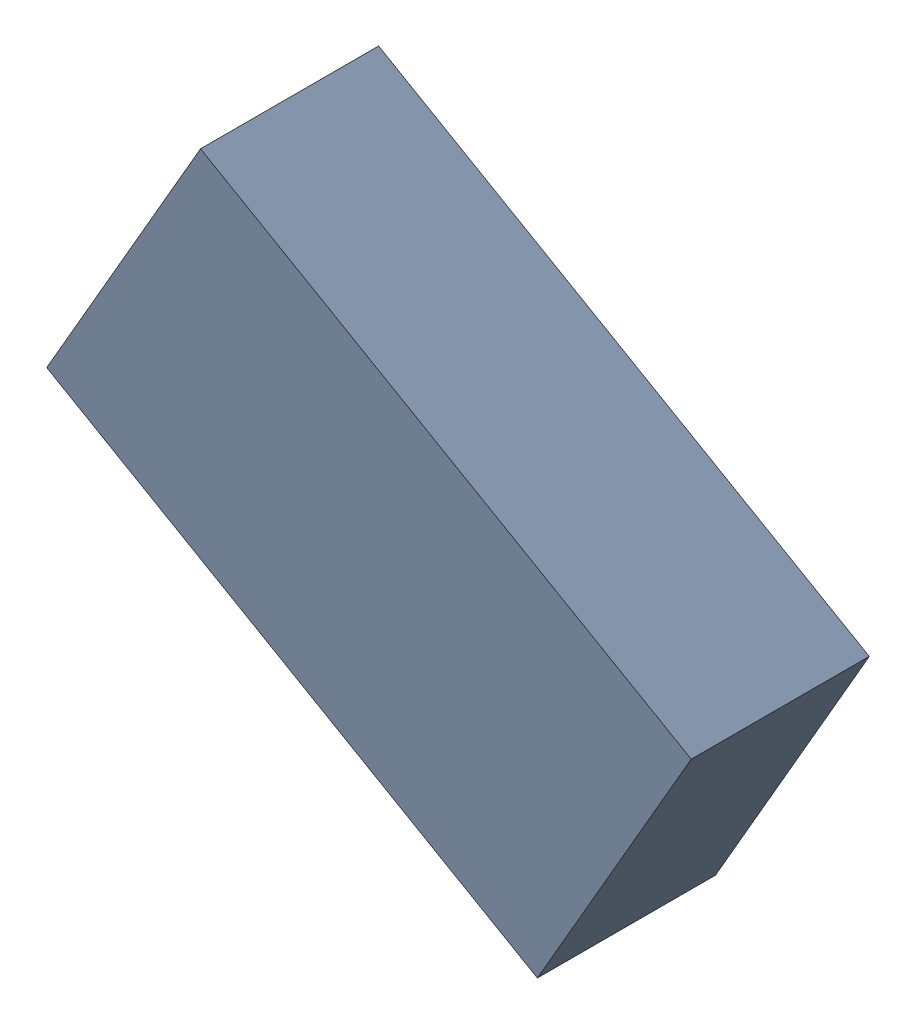
SolidWorks assembly L2_TDA3, configuration Standard. Lengths in mm.
Overall size (1.99 1.7 0.55).
2 component instances, 1 part files, 0 mates.
Components (placement in the parent):
- 885543872-1: 885543872 [Standard] at (49.572 -33.6901 0) size (1.99 1.7 0.55)
  - Extruded_20-1: Extruded_20 [Standard] at origin size (1.99 1.7 0.55)
